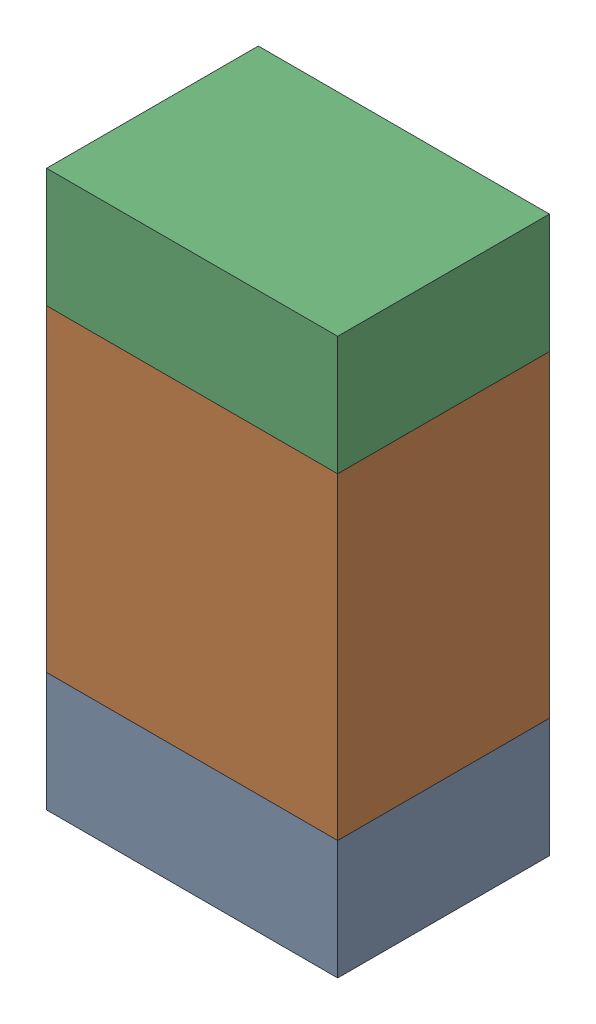
SolidWorks assembly R105_2PCB, configuration Default. Lengths in mm.
Overall size (0.55 1.05 0.4).
6 component instances, 2 part files, 0 mates.
Components (placement in the parent):
- 846483288-1: 846483288 [Default] at (117.5999 89.3876 0) size (0.55 0.22 0.4)
  - Extruded_12-1: Extruded_12 [Default] at origin size (0.55 0.22 0.4)
- 846483424-1: 846483424 [Default] at (117.5999 89.8001 0) size (0.55 0.6 0.4)
  - Extruded_13-1: Extruded_13 [Default] at origin size (0.55 0.6 0.4)
- 846483288-2: 846483288 [Default] at (117.5999 90.2126 0) size (0.55 0.22 0.4)
  - Extruded_12-1: Extruded_12 [Default] at origin size (0.55 0.22 0.4)
